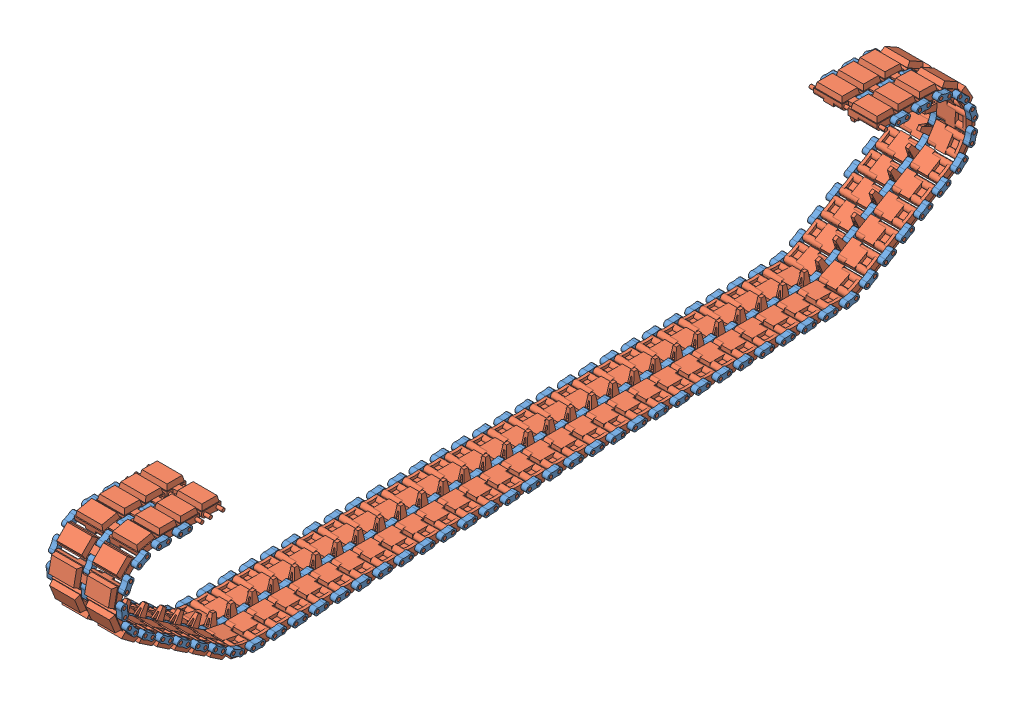
SolidWorks assembly montagem esteira direita 1, configuration Valor predeterminado. Lengths in mm.
Overall size (17.75 35.98 204.42).
109 component instances, 3 part files, 0 mates.
Components (placement in the parent):
- caminho da esteira direita-1: caminho da esteira direita [Valor predeterminado] at origin
- 3 uniões-1: 3 uniões [Valor predeterminado] at (-39.6 -12.3275 -1.7901) x (1 0 0) z (0 -0.082952 0.996554) size (17.75 1.5 3.5)
- tracks-1: tracks [Valor predeterminado] at (-39.6 -12.203 -1.785) size (17.75 5.2 4.5)
- 3 uniões-2: 3 uniões [Valor predeterminado] at (-39.6 -12.3275 -6.7901) x (1 0 0) z (0 -0.082952 0.996554) size (17.75 1.5 3.5)
- 3 uniões-3: 3 uniões [Valor predeterminado] at (-39.6 -12.3275 -11.7901) x (1 0 0) z (0 -0.082952 0.996554) size (17.75 1.5 3.5)
- 3 uniões-4: 3 uniões [Valor predeterminado] at (-39.6 -12.3275 -16.7901) x (1 0 0) z (0 -0.082952 0.996554) size (17.75 1.5 3.5)
- 3 uniões-5: 3 uniões [Valor predeterminado] at (-39.6 -12.3275 -21.7901) x (1 0 0) z (0 -0.082952 0.996554) size (17.75 1.5 3.5)
- 3 uniões-6: 3 uniões [Valor predeterminado] at (-39.6 -12.3275 -26.7901) x (1 0 0) z (0 -0.082952 0.996554) size (17.75 1.5 3.5)
- 3 uniões-7: 3 uniões [Valor predeterminado] at (-39.6 -12.3275 -31.7901) x (1 0 0) z (0 -0.082952 0.996554) size (17.75 1.5 3.5)
- 3 uniões-8: 3 uniões [Valor predeterminado] at (-39.6 -12.3275 -36.7901) x (1 0 0) z (0 -0.082952 0.996554) size (17.75 1.5 3.5)
- 3 uniões-9: 3 uniões [Valor predeterminado] at (-39.6 -12.3275 -41.7901) x (1 0 0) z (0 -0.082952 0.996554) size (17.75 1.5 3.5)
- 3 uniões-10: 3 uniões [Valor predeterminado] at (-39.6 -12.3275 -46.7901) x (1 0 0) z (0 -0.082952 0.996554) size (17.75 1.5 3.5)
- 3 uniões-11: 3 uniões [Valor predeterminado] at (-39.6 -12.3275 -51.7901) x (1 0 0) z (0 -0.082952 0.996554) size (17.75 1.5 3.5)
- 3 uniões-12: 3 uniões [Valor predeterminado] at (-39.6 -12.3275 -56.7901) x (1 0 0) z (0 -0.082952 0.996554) size (17.75 1.5 3.5)
- 3 uniões-13: 3 uniões [Valor predeterminado] at (-39.6 -12.3275 -61.7901) x (1 0 0) z (0 -0.082952 0.996554) size (17.75 1.5 3.5)
- 3 uniões-14: 3 uniões [Valor predeterminado] at (-39.6 -12.3275 -66.7901) x (1 0 0) z (0 -0.082952 0.996554) size (17.75 1.5 3.5)
- 3 uniões-15: 3 uniões [Valor predeterminado] at (-39.6 -12.3275 -71.7901) x (1 0 0) z (0 -0.082952 0.996554) size (17.75 1.5 3.5)
- 3 uniões-16: 3 uniões [Valor predeterminado] at (-39.6 -12.3275 -76.7901) x (1 0 0) z (0 -0.082952 0.996554) size (17.75 1.5 3.5)
- 3 uniões-17: 3 uniões [Valor predeterminado] at (-39.6 -12.3275 -81.7901) x (1 0 0) z (0 -0.082952 0.996554) size (17.75 1.5 3.5)
- 3 uniões-18: 3 uniões [Valor predeterminado] at (-39.6 -12.3275 -86.7901) x (1 0 0) z (0 -0.082952 0.996554) size (17.75 1.5 3.5)
- 3 uniões-19: 3 uniões [Valor predeterminado] at (-39.6 -12.3275 -91.7901) x (1 0 0) z (0 -0.082952 0.996554) size (17.75 1.5 3.5)
- 3 uniões-20: 3 uniões [Valor predeterminado] at (-39.6 -12.3275 -96.7901) x (1 0 0) z (0 -0.082952 0.996554) size (17.75 1.5 3.5)
- 3 uniões-21: 3 uniões [Valor predeterminado] at (-39.6 -12.3275 -101.7901) x (1 0 0) z (0 -0.082952 0.996554) size (17.75 1.5 3.5)
- 3 uniões-22: 3 uniões [Valor predeterminado] at (-39.6 -12.3275 -106.7901) x (1 0 0) z (0 -0.082952 0.996554) size (17.75 1.5 3.5)
- 3 uniões-23: 3 uniões [Valor predeterminado] at (-39.6 -12.3275 -111.7901) x (1 0 0) z (0 -0.082952 0.996554) size (17.75 1.5 3.5)
- 3 uniões-24: 3 uniões [Valor predeterminado] at (-39.6 -12.3275 -116.7901) x (1 0 0) z (0 -0.082952 0.996554) size (17.75 1.5 3.5)
- 3 uniões-25: 3 uniões [Valor predeterminado] at (-39.6 -12.3275 -121.7901) x (1 0 0) z (0 -0.082952 0.996554) size (17.75 1.5 3.5)
- 3 uniões-26: 3 uniões [Valor predeterminado] at (-39.6 -12.3275 -126.7901) x (1 0 0) z (0 -0.082952 0.996554) size (17.75 1.5 3.5)
- 3 uniões-27: 3 uniões [Valor predeterminado] at (-39.6 -12.3275 -131.7901) x (1 0 0) z (0 -0.082952 0.996554) size (17.75 1.5 3.5)
- tracks-2: tracks [Valor predeterminado] at (-39.6 -12.203 -6.785) size (17.75 5.2 4.5)
- tracks-3: tracks [Valor predeterminado] at (-39.6 -12.203 -11.785) size (17.75 5.2 4.5)
- tracks-4: tracks [Valor predeterminado] at (-39.6 -12.203 -16.785) size (17.75 5.2 4.5)
- tracks-5: tracks [Valor predeterminado] at (-39.6 -12.203 -21.785) size (17.75 5.2 4.5)
- tracks-6: tracks [Valor predeterminado] at (-39.6 -12.203 -26.785) size (17.75 5.2 4.5)
- tracks-7: tracks [Valor predeterminado] at (-39.6 -12.203 -31.785) size (17.75 5.2 4.5)
- tracks-8: tracks [Valor predeterminado] at (-39.6 -12.203 -36.785) size (17.75 5.2 4.5)
- tracks-9: tracks [Valor predeterminado] at (-39.6 -12.203 -41.785) size (17.75 5.2 4.5)
- tracks-10: tracks [Valor predeterminado] at (-39.6 -12.203 -46.785) size (17.75 5.2 4.5)
- tracks-11: tracks [Valor predeterminado] at (-39.6 -12.203 -51.785) size (17.75 5.2 4.5)
- tracks-12: tracks [Valor predeterminado] at (-39.6 -12.203 -56.785) size (17.75 5.2 4.5)
- tracks-13: tracks [Valor predeterminado] at (-39.6 -12.203 -61.785) size (17.75 5.2 4.5)
- tracks-14: tracks [Valor predeterminado] at (-39.6 -12.203 -66.785) size (17.75 5.2 4.5)
- tracks-15: tracks [Valor predeterminado] at (-39.6 -12.203 -71.785) size (17.75 5.2 4.5)
- tracks-16: tracks [Valor predeterminado] at (-39.6 -12.203 -76.785) size (17.75 5.2 4.5)
- tracks-17: tracks [Valor predeterminado] at (-39.6 -12.203 -81.785) size (17.75 5.2 4.5)
- tracks-18: tracks [Valor predeterminado] at (-39.6 -12.203 -86.785) size (17.75 5.2 4.5)
- tracks-19: tracks [Valor predeterminado] at (-39.6 -12.203 -91.785) size (17.75 5.2 4.5)
- tracks-20: tracks [Valor predeterminado] at (-39.6 -12.203 -96.785) size (17.75 5.2 4.5)
- tracks-21: tracks [Valor predeterminado] at (-39.6 -12.203 -101.785) size (17.75 5.2 4.5)
- tracks-22: tracks [Valor predeterminado] at (-39.6 -12.203 -106.785) size (17.75 5.2 4.5)
- tracks-23: tracks [Valor predeterminado] at (-39.6 -12.203 -111.785) size (17.75 5.2 4.5)
- tracks-24: tracks [Valor predeterminado] at (-39.6 -12.203 -116.785) size (17.75 5.2 4.5)
- tracks-25: tracks [Valor predeterminado] at (-39.6 -12.203 -121.785) size (17.75 5.2 4.5)
- tracks-26: tracks [Valor predeterminado] at (-39.6 -12.203 -126.785) size (17.75 5.2 4.5)
- tracks-27: tracks [Valor predeterminado] at (-39.6 -12.203 -131.785) size (17.75 5.2 4.5)
- tracks-28: tracks [Valor predeterminado] at (-39.6 -11.8951 3.1866) x (1 0 0) z (0 0.193729 0.981055) size (17.75 5.2 4.5)
- 3 uniões-28: 3 uniões [Valor predeterminado] at (-39.6 -12.1727 3.2149) x (1 0 0) z (0 0.008663 0.999962) size (17.75 1.5 3.5)
- tracks-29: tracks [Valor predeterminado] at (-39.6 4.024 28.4515) x (1 0 0) z (0 0.598283 0.801285) size (17.75 5.2 4.5)
- tracks-30: tracks [Valor predeterminado] at (-39.6 -9.9699 7.7372) x (1 0 0) z (0 0.557298 0.830313) size (17.75 5.2 4.5)
- 3 uniões-29: 3 uniões [Valor predeterminado] at (-39.6 -10.2069 7.867) x (1 0 0) z (0 0.399314 0.916814) size (17.75 1.5 3.5)
- 3 uniões-30: 3 uniões [Valor predeterminado] at (-39.6 -7.1835 11.8888) x (1 0 0) z (0 0.557298 0.830313) size (17.75 1.5 3.5)
- tracks-31: tracks [Valor predeterminado] at (-39.6 -7.1835 11.8888) x (1 0 0) z (0 0.557298 0.830313) size (17.75 5.2 4.5)
- tracks-32: tracks [Valor predeterminado] at (-39.6 -4.397 16.0404) x (1 0 0) z (0 0.557298 0.830313) size (17.75 5.2 4.5)
- tracks-33: tracks [Valor predeterminado] at (-39.6 -1.6105 20.1919) x (1 0 0) z (0 0.557298 0.830313) size (17.75 5.2 4.5)
- tracks-34: tracks [Valor predeterminado] at (-39.6 1.176 24.3435) x (1 0 0) z (0 0.557298 0.830313) size (17.75 5.2 4.5)
- 3 uniões-31: 3 uniões [Valor predeterminado] at (-39.6 -4.397 16.0404) x (1 0 0) z (0 0.557298 0.830313) size (17.75 1.5 3.5)
- 3 uniões-32: 3 uniões [Valor predeterminado] at (-39.6 -1.6105 20.1919) x (1 0 0) z (0 0.557298 0.830313) size (17.75 1.5 3.5)
- 3 uniões-33: 3 uniões [Valor predeterminado] at (-39.6 1.176 24.3435) x (1 0 0) z (0 0.557298 0.830313) size (17.75 1.5 3.5)
- 3 uniões-35: 3 uniões [Valor predeterminado] at (-39.6 3.9625 28.4951) x (1 0 0) z (0 0.557298 0.830313) size (17.75 1.5 3.5)
- tracks-35: tracks [Valor predeterminado] at (-39.6 7.8717 31.4681) x (1 0 0) z (0 0.926852 0.375428) size (17.75 5.2 4.5)
- tracks-36: tracks [Valor predeterminado] at (-39.6 12.724 31.9236) x (1 0 0) z (0 0.980528 -0.196381) size (17.75 5.2 4.5)
- 3 uniões-36: 3 uniões [Valor predeterminado] at (-39.6 7.6514 31.8436) x (1 0 0) z (0 0.780007 0.625771) size (17.75 1.5 3.5)
- 3 uniões-37: 3 uniões [Valor predeterminado] at (-39.6 12.7466 32.3584) x (1 0 0) z (0 0.995623 0.093459) size (17.75 1.5 3.5)
- 3 uniões-38: 3 uniões [Valor predeterminado] at (-39.6 17.2847 29.9852) x (1 0 0) z (0 0.882837 -0.46968) size (17.75 1.5 3.5)
- tracks-37: tracks [Valor predeterminado] at (-39.6 17.0266 29.6346) x (1 0 0) z (0 0.71078 -0.703414) size (17.75 5.2 4.5)
- 3 uniões-39: 3 uniões [Valor predeterminado] at (-39.6 19.7688 25.5068) x (1 0 0) z (0 0.47885 -0.877897) size (17.75 1.5 3.5)
- 3 uniões-40: 3 uniões [Valor predeterminado] at (-39.6 19.6608 20.3884) x (1 0 0) z (0 -0.002718 -0.999996) size (17.75 1.5 3.5)
- tracks-38: tracks [Valor predeterminado] at (-39.6 19.3604 25.356) x (1 0 0) z (0 0.206584 -0.978429) size (17.75 5.2 4.5)
- tracks-39: tracks [Valor predeterminado] at (-39.6 19.6606 20.3884) x (1 0 0) z (0 -0.002819 -0.999996) size (17.75 5.2 4.5)
- 3 uniões-41: 3 uniões [Valor predeterminado] at (-39.6 19.7329 15.3892) x (1 0 0) z (0 0.021868 -0.999761) size (17.75 1.5 3.5)
- tracks-40: tracks [Valor predeterminado] at (-39.6 19.6465 15.3884) x (1 0 0) z (0 -0.002819 -0.999996) size (17.75 5.2 4.5)
- tracks-41: tracks [Valor predeterminado] at (-39.6 19.6324 10.3884) x (1 0 0) z (0 -0.002819 -0.999996) size (17.75 5.2 4.5)
- 3 uniões-42: 3 uniões [Valor predeterminado] at (-39.6 -12.4454 -136.8075) x (1 0 0) z (0 -0.202998 0.979179) size (17.75 1.5 3.5)
- 3 uniões-43: 3 uniões [Valor predeterminado] at (-39.6 -11.2277 -141.6617) x (1 0 0) z (0 -0.512318 0.858796) size (17.75 1.5 3.5)
- tracks-66: tracks [Valor predeterminado] at (-39.6 -11.097 -141.5923) x (1 0 0) z (0 -0.425216 0.905092) size (17.75 5.2 4.5)
- tracks-67: tracks [Valor predeterminado] at (-39.6 -12.089 -136.7772) x (1 0 0) z (0 0.034582 0.999402) size (17.75 5.2 4.5)
- tracks-68: tracks [Valor predeterminado] at (-39.6 -8.6661 -145.9557) x (1 0 0) z (0 -0.512318 0.858796) size (17.75 5.2 4.5)
- 3 uniões-44: 3 uniões [Valor predeterminado] at (-39.6 -8.6661 -145.9557) x (1 0 0) z (0 -0.512318 0.858796) size (17.75 1.5 3.5)
- 3 uniões-45: 3 uniões [Valor predeterminado] at (-39.6 -6.1045 -150.2497) x (1 0 0) z (0 -0.512318 0.858796) size (17.75 1.5 3.5)
- 3 uniões-46: 3 uniões [Valor predeterminado] at (-39.6 -3.5429 -154.5436) x (1 0 0) z (0 -0.512318 0.858796) size (17.75 1.5 3.5)
- tracks-69: tracks [Valor predeterminado] at (-39.6 -6.1045 -150.2497) x (1 0 0) z (0 -0.512318 0.858796) size (17.75 5.2 4.5)
- tracks-70: tracks [Valor predeterminado] at (-39.6 -3.5429 -154.5436) x (1 0 0) z (0 -0.512318 0.858796) size (17.75 5.2 4.5)
- tracks-71: tracks [Valor predeterminado] at (-39.6 -0.9813 -158.8376) x (1 0 0) z (0 -0.512318 0.858796) size (17.75 5.2 4.5)
- tracks-72: tracks [Valor predeterminado] at (-39.6 1.5944 -163.123) x (1 0 0) z (0 -0.521765 0.853089) size (17.75 5.2 4.5)
- tracks-73: tracks [Valor predeterminado] at (-39.6 4.9755 -166.7004) x (1 0 0) z (0 -0.842395 0.538861) size (17.75 5.2 4.5)
- tracks-74: tracks [Valor predeterminado] at (-39.6 9.6503 -168.1367) x (1 0 0) z (0 -0.999633 0.027097) size (17.75 5.2 4.5)
- 3 uniões-47: 3 uniões [Valor predeterminado] at (-39.6 -0.9813 -158.8376) x (1 0 0) z (0 -0.512318 0.858796) size (17.75 1.5 3.5)
- 3 uniões-48: 3 uniões [Valor predeterminado] at (-39.6 1.376 -163.2856) x (1 0 0) z (0 -0.667407 0.744694) size (17.75 1.5 3.5)
- 3 uniões-49: 3 uniões [Valor predeterminado] at (-39.6 4.8052 -167.0681) x (1 0 0) z (0 -0.955899 0.293697) size (17.75 1.5 3.5)
- 3 uniões-50: 3 uniões [Valor predeterminado] at (-39.6 9.6942 -168.5396) x (1 0 0) z (0 -0.970406 -0.241481) size (17.75 1.5 3.5)
- tracks-75: tracks [Valor predeterminado] at (-39.6 14.3961 -166.9557) x (1 0 0) z (0 -0.87035 -0.492433) size (17.75 5.2 4.5)
- tracks-76: tracks [Valor predeterminado] at (-39.6 17.8526 -163.496) x (1 0 0) z (0 -0.491603 -0.870819) size (17.75 5.2 4.5)
- 3 uniões-51: 3 uniões [Valor predeterminado] at (-39.6 18.2291 -163.6457) x (1 0 0) z (0 -0.240556 -0.970635) size (17.75 1.5 3.5)
- 3 uniões-52: 3 uniões [Valor predeterminado] at (-39.6 14.6415 -167.2782) x (1 0 0) z (0 -0.70677 -0.707444) size (17.75 1.5 3.5)
- tracks-77: tracks [Valor predeterminado] at (-39.6 19.1155 -158.7491) x (1 0 0) z (0 -0.029601 -0.999562) size (17.75 5.2 4.5)
- tracks-78: tracks [Valor predeterminado] at (-39.6 19.1698 -153.7498) x (1 0 0) z (0 -0.002819 -0.999996) size (17.75 5.2 4.5)
- 3 uniões-53: 3 uniões [Valor predeterminado] at (-39.6 19.1557 -158.7498) x (1 0 0) z (0 -0.002819 -0.999996) size (17.75 1.5 3.5)
- 3 uniões-54: 3 uniões [Valor predeterminado] at (-39.6 19.1698 -153.7498) x (1 0 0) z (0 -0.002819 -0.999996) size (17.75 1.5 3.5)
- tracks-79: tracks [Valor predeterminado] at (-39.6 19.1838 -148.7498) x (1 0 0) z (0 -0.002819 -0.999996) size (17.75 5.2 4.5)
